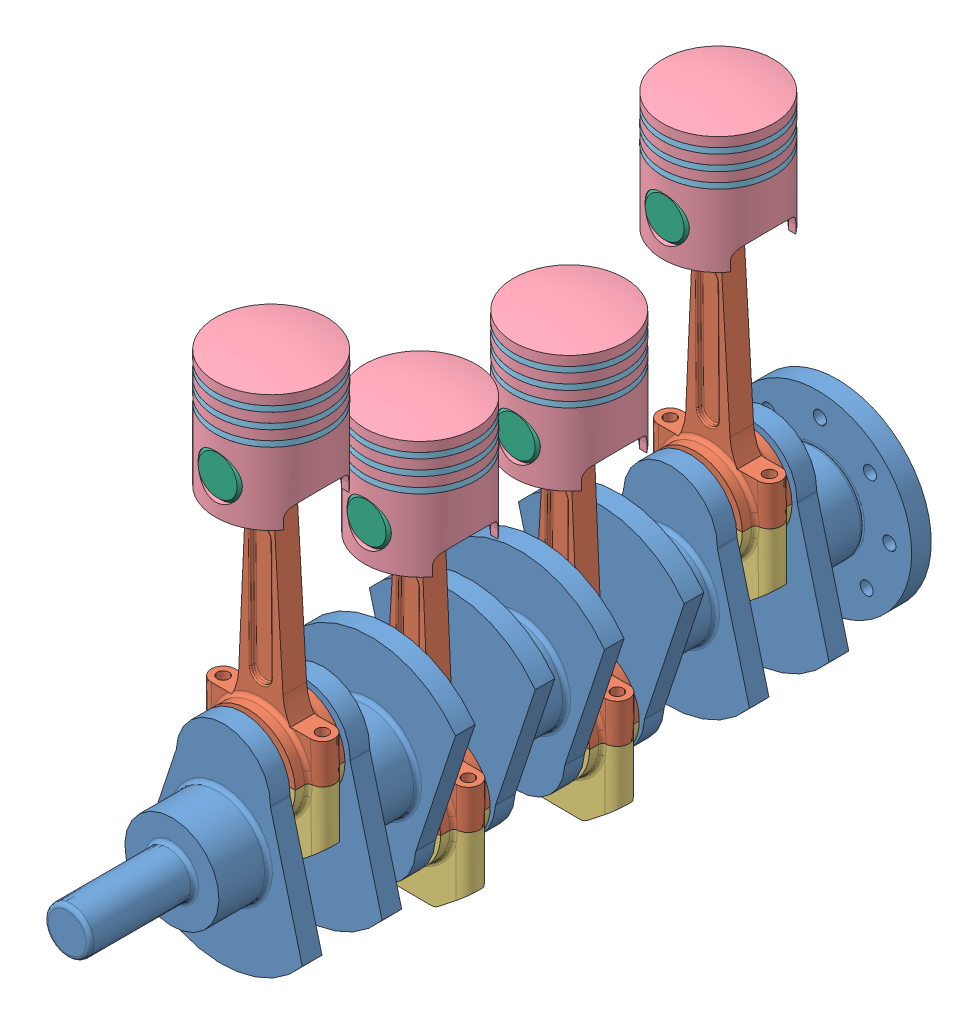
SolidWorks assembly Assemble Four Cylinder Engine, configuration Default. Lengths in mm.
Overall size (149.09 417.48 589).
29 component instances, 6 part files, 66 mates.
Components (placement in the parent):
- Crankshaft-1: Crankshaft [Default] at (0 0 456) x (-0.999478 0.032291 0) z (0 0 1) size (144 160 589)
- connecting rod-1: connecting rod [Default] at (0 245.172 433) x (0.999975 0.007062 0) z (0 0 1) size (94 223.7 38)
- connecting rod cap-1: connecting rod cap [Default] at (1.4208 43.9771 433) x (0.999975 0.007062 0) z (0 0 -1) size (94 60 38)
- Piston-1: Piston [Default] at (0 218.172 433) x (-1 0 0) z (0 0 -1) size (85 95 85)
- Piston Ring-1: Piston Ring [Default] at (0 300.872 433) x (0.929827 0 -0.367997) z (0 -1 0) size (85 85 4.3)
- piston pin-1: piston pin [Default] at (0 245.172 433) x (-0.999741 0.02276 0) z (0 0 -1) size (33.8 33.8 82)
- Piston Ring-6: Piston Ring [Default] at (0 284.972 433) x (0.703682 0 -0.710516) z (0 1 0) size (85 85 4.3)
- Piston Ring-10: Piston Ring [Default] at (0 273.372 433) x (0.824973 0 -0.565172) z (0 1 0) size (85 85 4.3)
- Piston-2: Piston [Default] at (0 130.2179 319) x (-1 0 0) z (0 0 -1) size (85 95 85)
- Piston Ring-12: Piston Ring [Default] at (0 212.9179 319) x (0.850415 0 -0.526113) z (0 -1 0) size (85 85 4.3)
- Piston Ring-13: Piston Ring [Default] at (0 197.0179 319) x (0.567442 0 -0.823413) z (0 1 0) size (85 85 4.3)
- Piston Ring-14: Piston Ring [Default] at (0 185.4179 319) x (0.712451 0 -0.701722) z (0 1 0) size (85 85 4.3)
- piston pin-2: piston pin [Default] at (0 157.2179 319) x (-0.194552 0.980892 0) z (0 0 -1) size (33.8 33.8 82)
- connecting rod-2: connecting rod [Default] at (0 157.2179 319) x (0.999975 -0.007062 0) z (0 0 1) size (94 223.7 38)
- connecting rod cap-3: connecting rod cap [Default] at (-1.4208 -43.9771 319) x (0.999975 -0.007062 0) z (0 0 -1) size (94 60 38)
- Piston-4: Piston [Default] at (0 130.2179 205) size (85 95 85)
- Piston Ring-18: Piston Ring [Default] at (0 212.9179 205) x (0.734145 0 -0.678992) z (0 -1 0) size (85 85 4.3)
- Piston Ring-19: Piston Ring [Default] at (0 197.0179 205) x (0.399554 0 -0.91671) z (0 1 0) size (85 85 4.3)
- Piston Ring-20: Piston Ring [Default] at (0 185.4179 205) x (0.565153 0 -0.824986) z (0 1 0) size (85 85 4.3)
- piston pin-4: piston pin [Default] at (0 157.2179 205) x (-0.991697 -0.128596 0) z (0 0 1) size (33.8 33.8 82)
- connecting rod-4: connecting rod [Default] at (0 157.2179 205) x (-0.999975 0.007062 0) z (0 0 -1) size (94 223.7 38)
- connecting rod cap-5: connecting rod cap [Default] at (-1.4208 -43.9771 205) x (-0.999975 0.007062 0) z (0 0 1) size (94 60 38)
- Piston-6: Piston [Default] at (0 218.172 91) size (85 95 85)
- Piston Ring-24: Piston Ring [Default] at (0 300.872 91) x (0.569535 0 -0.821967) z (0 -1 0) size (85 85 4.3)
- Piston Ring-25: Piston Ring [Default] at (0 284.972 91) x (0.191375 0 -0.981517) z (0 1 0) size (85 85 4.3)
- Piston Ring-26: Piston Ring [Default] at (0 273.372 91) x (0.372918 0 -0.927864) z (0 1 0) size (85 85 4.3)
- piston pin-6: piston pin [Default] at (0 245.172 91) x (0.519581 -0.854421 0) z (0 0 1) size (33.8 33.8 82)
- connecting rod-6: connecting rod [Default] at (0 245.172 91) x (-0.999975 -0.007062 0) z (0 0 -1) size (94 223.7 38)
- connecting rod cap-7: connecting rod cap [Default] at (1.4208 43.9771 91) x (-0.999975 -0.007062 0) z (0 0 1) size (94 60 38)
Mates (geometry in assembly coordinates):
- Concentric1: concentric anti-aligned: cylinder of Crankshaft-1 through (0 0 589) axis (0 0 -1) radius 17.5
- Coincident2: coincident: plane of Crankshaft-1 through (0 0 589) normal (0 0 1)
- Coincident4: coincident aligned: plane of Piston-1 through (0 218.172 433) normal (0 0 -1); plane of piston pin-1 through (0 245.172 433) normal (0 0 -1)
- Concentric2: concentric anti-aligned: cylinder of Piston-1 through (0 245.172 475.5) axis (0 0 -1) radius 16.9; cylinder of piston pin-1 through (0 245.172 392) axis (0 0 1) radius 16.9
- Concentric8: concentric anti-aligned: cylinder of Piston-1 through (0 308.172 433) axis (0 -1 0) radius 42.5; cylinder of Piston Ring-1 through (0 296.572 433) axis (0 1 0) radius 42.5
- Coincident5: coincident anti-aligned: plane of Piston-1 through (0 296.572 433) normal (0 1 0); circle of Piston Ring-1
- Concentric13: concentric anti-aligned: cylinder of Piston-1 through (0 284.972 433) axis (0 1 0) radius 39.5; cylinder of Piston Ring-6 through (0 289.272 433) axis (0 -1 0) radius 42.5
- Coincident7: coincident anti-aligned: plane of Piston-1 through (0 289.272 433) normal (0 -1 0); circle of Piston Ring-6
- Concentric17: concentric anti-aligned: cylinder of Piston-1 through (0 273.372 433) axis (0 1 0) radius 39.5; cylinder of Piston Ring-10 through (0 277.672 433) axis (0 -1 0) radius 42.5
- Coincident14: coincident anti-aligned: plane of Piston-1 through (0 277.672 433) normal (0 -1 0); circle of Piston Ring-10
- Coincident19: coincident anti-aligned: plane of connecting rod-1 through (0 245.172 433) normal (0 0 1); plane of Piston-1 through (0 218.172 433) normal (0 0 -1)
- Concentric25: concentric anti-aligned: cylinder of connecting rod-1 through (0 245.172 452) axis (0 0 -1) radius 16.9; cylinder of piston pin-1 through (0 245.172 392) axis (0 0 1) radius 16.9
- Concentric26: concentric aligned: cylinder of connecting rod-1 through (39.4199 44.2454 433) axis (-0.007062 0.999975 0) radius 4.5; cylinder of connecting rod cap-1 through (39.8436 -15.7531 433) axis (-0.007062 0.999975 0) radius 4.5
- Concentric27: concentric aligned: cylinder of connecting rod-1 through (-36.5782 43.7087 433) axis (-0.007062 0.999975 0) radius 4.5; cylinder of connecting rod cap-1 through (-36.1545 -16.2898 433) axis (-0.007062 0.999975 0) radius 4.5
- Coincident20: coincident anti-aligned: plane of connecting rod-1 through (1.4208 43.9771 452) normal (0.007062 -0.999975 0); plane of connecting rod cap-1 through (-34.5783 43.7228 414) normal (-0.007062 0.999975 0)
- Width2: width anti-aligned: plane of Crankshaft-1 through (0 0 456) normal (0 0 -1); plane of connecting rod-1 through (0 0 410) normal (0 0 1); plane of Crankshaft-1 through (0 245.172 442) normal (0 0 1); plane of connecting rod-1 through (0 245.172 424) normal (0 0 -1)
- Concentric28: concentric anti-aligned: cylinder of Crankshaft-1 through (1.4208 43.9771 410) axis (0 0 1) radius 27; cylinder of connecting rod-1 through (1.4208 43.9771 452) axis (0 0 -1) radius 27
- Concentric29: concentric anti-aligned: cylinder of Piston-1 through (0 308.172 433) axis (0 -1 0) radius 42.5
- Coincident22: coincident aligned: plane of Piston-2 through (0 130.2179 319) normal (0 0 -1); plane of piston pin-2 through (0 157.2179 319) normal (0 0 -1)
- Concentric30: concentric anti-aligned: cylinder of Piston-2 through (0 157.2179 361.5) axis (0 0 -1) radius 16.9; cylinder of piston pin-2 through (0 157.2179 278) axis (0 0 1) radius 16.9
- Concentric31: concentric anti-aligned: cylinder of Piston-2 through (0 220.2179 319) axis (0 -1 0) radius 42.5; cylinder of Piston Ring-12 through (0 208.6179 319) axis (0 1 0) radius 42.5
- Coincident23: coincident anti-aligned: plane of Piston-2 through (0 208.6179 319) normal (0 1 0); circle of Piston Ring-12
- Concentric32: concentric anti-aligned: cylinder of Piston-2 through (0 197.0179 319) axis (0 1 0) radius 39.5; cylinder of Piston Ring-13 through (0 201.3179 319) axis (0 -1 0) radius 42.5
- Coincident24: coincident anti-aligned: plane of Piston-2 through (0 201.3179 319) normal (0 -1 0); circle of Piston Ring-13
- Concentric33: concentric anti-aligned: cylinder of Piston-2 through (0 185.4179 319) axis (0 1 0) radius 39.5; cylinder of Piston Ring-14 through (0 189.7179 319) axis (0 -1 0) radius 42.5
- Coincident25: coincident anti-aligned: plane of Piston-2 through (0 189.7179 319) normal (0 -1 0); circle of Piston Ring-14
- Coincident26: coincident anti-aligned: plane of Piston-2 through (0 130.2179 319) normal (0 0 -1); plane of connecting rod-2 through (0 157.2179 319) normal (0 0 1)
- Concentric34: concentric anti-aligned: cylinder of piston pin-2 through (0 157.2179 278) axis (0 0 1) radius 16.9; cylinder of connecting rod-2 through (0 157.2179 338) axis (0 0 -1) radius 16.9
- Concentric35: concentric aligned: cylinder of connecting rod-2 through (36.5782 -44.2454 319) axis (0.007062 0.999975 0) radius 4.5; cylinder of connecting rod cap-3 through (36.1545 -104.2439 319) axis (0.007062 0.999975 0) radius 4.5
- Concentric36: concentric aligned: cylinder of connecting rod-2 through (-39.4199 -43.7087 319) axis (0.007062 0.999975 0) radius 4.5; cylinder of connecting rod cap-3 through (-39.8436 -103.7072 319) axis (0.007062 0.999975 0) radius 4.5
- Coincident27: coincident anti-aligned: plane of connecting rod-2 through (-1.4208 -43.9771 338) normal (-0.007062 -0.999975 0); plane of connecting rod cap-3 through (-37.4199 -43.7228 300) normal (0.007062 0.999975 0)
- Width3: width anti-aligned: plane of Crankshaft-1 through (0 0 296) normal (0 0 1); plane of connecting rod-2 through (0 0 342) normal (0 0 -1); plane of Crankshaft-1 through (0 157.2179 328) normal (0 0 1); plane of connecting rod-2 through (0 157.2179 310) normal (0 0 -1)
- Concentric37: concentric anti-aligned: cylinder of Crankshaft-1 through (-1.4208 -43.9771 296) axis (0 0 1) radius 27; cylinder of connecting rod-2 through (-1.4208 -43.9771 338) axis (0 0 -1) radius 27
- Concentric38: concentric anti-aligned: cylinder of Piston-2 through (0 220.2179 319) axis (0 -1 0) radius 42.5
- Coincident34: coincident aligned: plane of Piston-4 through (0 130.2179 205) normal (0 0 1); plane of piston pin-4 through (0 157.2179 205) normal (0 0 1)
- Concentric46: concentric anti-aligned: cylinder of Piston-4 through (0 157.2179 162.5) axis (0 0 1) radius 16.9; cylinder of piston pin-4 through (0 157.2179 246) axis (0 0 -1) radius 16.9
- Concentric47: concentric anti-aligned: cylinder of Piston-4 through (0 220.2179 205) axis (0 -1 0) radius 42.5; cylinder of Piston Ring-18 through (0 208.6179 205) axis (0 1 0) radius 42.5
- Coincident35: coincident anti-aligned: plane of Piston-4 through (0 208.6179 205) normal (0 1 0); circle of Piston Ring-18
- Concentric48: concentric anti-aligned: cylinder of Piston-4 through (0 197.0179 205) axis (0 1 0) radius 39.5; cylinder of Piston Ring-19 through (0 201.3179 205) axis (0 -1 0) radius 42.5
- Coincident36: coincident anti-aligned: plane of Piston-4 through (0 201.3179 205) normal (0 -1 0); circle of Piston Ring-19
- Concentric49: concentric anti-aligned: cylinder of Piston-4 through (0 185.4179 205) axis (0 1 0) radius 39.5; cylinder of Piston Ring-20 through (0 189.7179 205) axis (0 -1 0) radius 42.5
- Coincident37: coincident anti-aligned: plane of Piston-4 through (0 189.7179 205) normal (0 -1 0); circle of Piston Ring-20
- Coincident38: coincident anti-aligned: plane of Piston-4 through (0 130.2179 205) normal (0 0 1); plane of connecting rod-4 through (0 157.2179 205) normal (0 0 -1)
- Concentric50: concentric anti-aligned: cylinder of piston pin-4 through (0 157.2179 246) axis (0 0 -1) radius 16.9; cylinder of connecting rod-4 through (0 157.2179 186) axis (0 0 1) radius 16.9
- Concentric51: concentric aligned: cylinder of connecting rod-4 through (-39.4199 -43.7087 205) axis (0.007062 0.999975 0) radius 4.5; cylinder of connecting rod cap-5 through (-39.8436 -103.7072 205) axis (0.007062 0.999975 0) radius 4.5
- Concentric52: concentric aligned: cylinder of connecting rod-4 through (36.5782 -44.2454 205) axis (0.007062 0.999975 0) radius 4.5; cylinder of connecting rod cap-5 through (36.1545 -104.2439 205) axis (0.007062 0.999975 0) radius 4.5
- Coincident39: coincident anti-aligned: plane of connecting rod-4 through (-1.4208 -43.9771 186) normal (-0.007062 -0.999975 0); plane of connecting rod cap-5 through (34.5783 -44.2313 224) normal (0.007062 0.999975 0)
- Width4: width anti-aligned: plane of Crankshaft-1 through (0 0 228) normal (0 0 -1); plane of connecting rod-4 through (0 0 182) normal (0 0 1); plane of Crankshaft-1 through (0 157.2179 196) normal (0 0 -1); plane of connecting rod-4 through (0 157.2179 214) normal (0 0 1)
- Concentric53: concentric anti-aligned: cylinder of Crankshaft-1 through (-1.4208 -43.9771 228) axis (0 0 -1) radius 27; cylinder of connecting rod-4 through (-1.4208 -43.9771 186) axis (0 0 1) radius 27
- Concentric54: concentric anti-aligned: cylinder of Piston-4 through (0 220.2179 205) axis (0 -1 0) radius 42.5
- Coincident46: coincident aligned: plane of Piston-6 through (0 218.172 91) normal (0 0 1); plane of piston pin-6 through (0 245.172 91) normal (0 0 1)
- Concentric62: concentric anti-aligned: cylinder of Piston-6 through (0 245.172 48.5) axis (0 0 1) radius 16.9; cylinder of piston pin-6 through (0 245.172 132) axis (0 0 -1) radius 16.9
- Concentric63: concentric anti-aligned: cylinder of Piston-6 through (0 308.172 91) axis (0 -1 0) radius 42.5; cylinder of Piston Ring-24 through (0 296.572 91) axis (0 1 0) radius 42.5
- Coincident47: coincident anti-aligned: plane of Piston-6 through (0 296.572 91) normal (0 1 0); circle of Piston Ring-24
- Concentric64: concentric anti-aligned: cylinder of Piston-6 through (0 284.972 91) axis (0 1 0) radius 39.5; cylinder of Piston Ring-25 through (0 289.272 91) axis (0 -1 0) radius 42.5
- Coincident48: coincident anti-aligned: plane of Piston-6 through (0 289.272 91) normal (0 -1 0); circle of Piston Ring-25
- Concentric65: concentric anti-aligned: cylinder of Piston-6 through (0 273.372 91) axis (0 1 0) radius 39.5; cylinder of Piston Ring-26 through (0 277.672 91) axis (0 -1 0) radius 42.5
- Coincident49: coincident anti-aligned: plane of Piston-6 through (0 277.672 91) normal (0 -1 0); circle of Piston Ring-26
- Coincident50: coincident anti-aligned: plane of Piston-6 through (0 218.172 91) normal (0 0 1); plane of connecting rod-6 through (0 245.172 91) normal (0 0 -1)
- Concentric66: concentric anti-aligned: cylinder of piston pin-6 through (0 245.172 132) axis (0 0 -1) radius 16.9; cylinder of connecting rod-6 through (0 245.172 72) axis (0 0 1) radius 16.9
- Concentric67: concentric aligned: cylinder of connecting rod-6 through (-36.5782 43.7087 91) axis (-0.007062 0.999975 0) radius 4.5; cylinder of connecting rod cap-7 through (-36.1545 -16.2898 91) axis (-0.007062 0.999975 0) radius 4.5
- Concentric68: concentric aligned: cylinder of connecting rod-6 through (39.4199 44.2454 91) axis (-0.007062 0.999975 0) radius 4.5; cylinder of connecting rod cap-7 through (39.8436 -15.7531 91) axis (-0.007062 0.999975 0) radius 4.5
- Coincident51: coincident anti-aligned: plane of connecting rod-6 through (1.4208 43.9771 72) normal (0.007062 -0.999975 0); plane of connecting rod cap-7 through (37.4199 44.2313 110) normal (-0.007062 0.999975 0)
- Width5: width anti-aligned: plane of Crankshaft-1 through (0 0 68) normal (0 0 1); plane of connecting rod-6 through (0 0 114) normal (0 0 -1); plane of Crankshaft-1 through (0 245.172 82) normal (0 0 -1); plane of connecting rod-6 through (0 245.172 100) normal (0 0 1)
- Concentric69: concentric anti-aligned: cylinder of Crankshaft-1 through (1.4208 43.9771 114) axis (0 0 -1) radius 27; cylinder of connecting rod-6 through (1.4208 43.9771 72) axis (0 0 1) radius 27
- Concentric70: concentric anti-aligned: cylinder of Piston-6 through (0 308.172 91) axis (0 -1 0) radius 42.5
